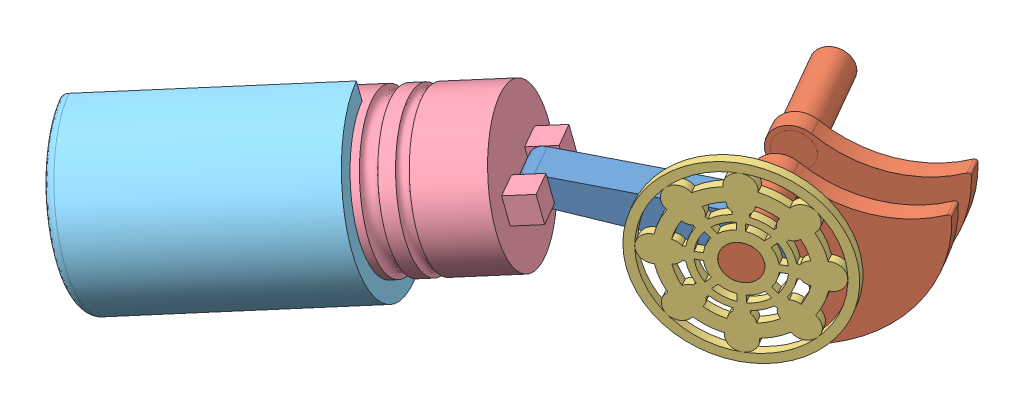
SolidWorks assembly Assembly-Piston Cylinder, configuration Default. Lengths in mm.
Overall size (809.08 340.7 571.6).
5 component instances, 5 part files, 9 mates.
Components (placement in the parent):
- Connecting rod-1: Connecting rod [Default] at (14.9006 -189.2053 212.3582) x (0.064714 0.997735 -0.018354) z (0.492444 -0.015932 0.870199) size (50 340 40)
- Crank-1: Crank [Default] at (-25.1959 -122.1555 213.2931) x (-0.541973 -0.787934 0.292275) z (0.492444 -0.015932 0.870199) size (191.6 175 280)
- Flywheel-1: Flywheel [Default] at (58.5195 -124.864 361.2268) x (0.870334 0.004195 -0.492444) z (0.492444 -0.015932 0.870199) size (200 200 10)
- Piston-1: Piston [Default] at (-264.7218 -194.7772 393.4772) x (-0.197269 0.971769 0.129426) z (0.492444 -0.015932 0.870199) size (160 275.87 160)
- Cylinder-1: Cylinder [Default] at (-475.7496 -253.3779 511.8245) x (-0.197269 0.971769 0.129426) z (0.492444 -0.015932 0.870199) size (200 260 200)
Mates (geometry in assembly coordinates):
- Coincident1: coincident: plane of Connecting rod-1 through (51.0975 -96.1527 239.5446) normal (0.492444 -0.015932 0.870199); plane of Piston-1 through (-144.0172 -148.9138 348.9937) normal (-0.492444 0.015932 -0.870199)
- Concentric1: concentric: cylinder of Connecting rod-1 through (-153.7736 -167.0213 354.1832) axis (-0.492444 0.015932 -0.870199) radius 10; cylinder of Piston-1 through (-187.3997 -165.9334 294.7624) axis (0.492444 -0.015932 0.870199) radius 10
- Concentric2: concentric: cylinder of Connecting rod-1 through (96.8562 -80.3239 213.9397) axis (-0.492444 0.015932 -0.870199) radius 20; cylinder of Crank-1 through (106.7051 -80.6425 231.3436) axis (-0.492444 0.015932 -0.870199) radius 20
- Coincident3: coincident: plane of Connecting rod-1 through (31.3998 -95.5154 204.7367) normal (-0.492444 0.015932 -0.870199); plane of Crank-1 through (8.5614 -192.003 215.8943) normal (0.492444 -0.015932 0.870199)
- Concentric3: concentric: cylinder of Crank-1 through (63.444 -125.0233 369.9288) axis (-0.492444 0.015932 -0.870199) radius 20; cylinder of Flywheel-1 through (63.444 -125.0233 369.9288) axis (-0.492444 0.015932 -0.870199) radius 20
- Coincident4: coincident: plane of Crank-1 through (63.444 -125.0233 369.9288) normal (0.492444 -0.015932 0.870199); plane of Flywheel-1 through (63.444 -125.0233 369.9288) normal (0.492444 -0.015932 0.870199)
- Concentric4: concentric: cylinder of Piston-1 through (-303.4919 -205.5433 415.22) axis (-0.847694 -0.235398 0.475398) radius 80; cylinder of Cylinder-1 through (-509.9019 -262.8617 530.9776) axis (-0.847694 -0.235398 0.475398) radius 80
- Distance1: distance = 350 mm: axis of Crank-1 through (-15.347 -122.4742 230.697) axis (-0.492444 0.015932 -0.870199); plane of Cylinder-1 through (-341.5864 -203.9075 344.8745) normal (0.847694 0.235398 -0.475398)
- Coincident9: coincident: axis of Crank-1 through (-15.347 -122.4742 230.697) axis (-0.492444 0.015932 -0.870199); plane of Cylinder-1 through (-475.7496 -253.3779 511.8245) normal (-0.197269 0.971769 0.129426)
